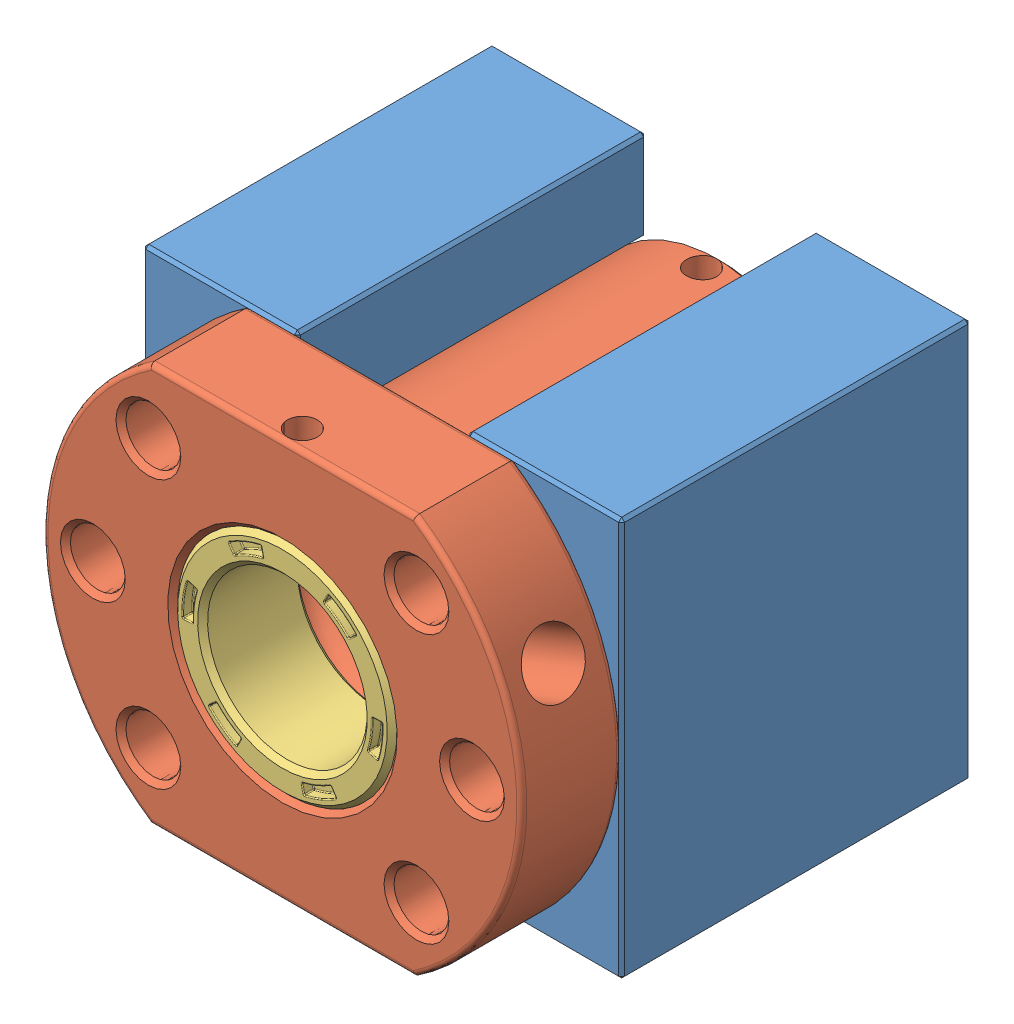
SolidWorks assembly Slider nut and adapter, configuration Default. Lengths in mm.
Overall size (48 40 45).
5 component instances, 4 part files, 4 mates.
Components (placement in the parent):
- Nut Housing HD16-1: Nut Housing HD16 [Default] at (-24 -0.3 0.3) x (1 0 0) z (0 0 -1) size (48 40 35)
- Ballscrew Nut SFU1605-1610-1: Ballscrew Nut SFU1605-1610 [SFU1605-3] at (-10 19.7 -33.2) x (1 0 0) z (0 -1 0) size (48 44 40)
  - SFU1605-1610-1-1: SFU1605-1610-1 [Default] at (-14 43.5 0) size (48 44 40)
  - SFU1605-1610-3-1: SFU1605-1610-3 [Default] at (-14 33.4998 0) x (-0.92388 0 0.382683) z (-0.382683 0 -0.92388) size (22.05 10 22)
  - SFU1605-1610-2-1: SFU1605-1610-2 [Default] at (-14 9.5 0) x (1 0 0) z (0 0 -1) size (22 10 22)
Mates (geometry in assembly coordinates):
- Concentric53: concentric anti-aligned: circle of Nut Housing HD16-1; circle of Ballscrew Nut SFU1605-1610-1/SFU1605-1610-1-1
- Coincident120: coincident anti-aligned: plane of Nut Housing HD16-1 through (-24 19.7 0.3) normal (0 0 1); plane of Ballscrew Nut SFU1605-1610-1/SFU1605-1610-1-1 through (-24 -4.3 0.3) normal (0 0 -1)
- Parallel55: parallel aligned: plane of Nut Housing HD16-1 through (-48 39.7 -34.7) normal (0 1 0); plane of Ballscrew Nut SFU1605-1610-1/SFU1605-1610-1-1 through (-37.2665 39.7 -33.701) normal (0 1 0)
- Coincident121: coincident: point of Nut Housing HD16-1; point of assembly
